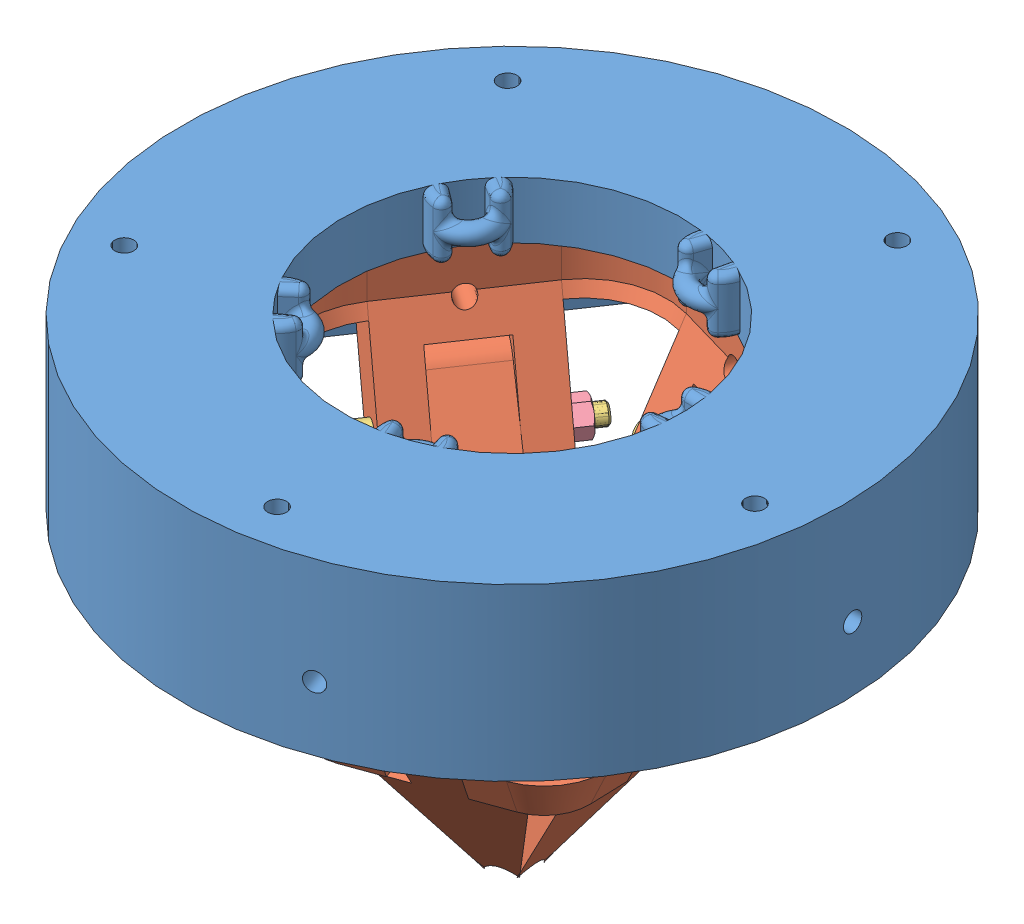
SolidWorks assembly Manipulator - pentagon v1, configuration Default. Lengths in mm.
Overall size (183.82 130.58 183.76).
19 component instances, 6 part files, 44 mates.
Components (placement in the parent):
- Rope-1: Rope [Default] at (264.0105 254.2057 492.1032) x (-0.958589 0 0.284792) z (-0.284792 0 -0.958589) (suppressed, hidden)
- Case - Pentagon-1: Case - Pentagon [Default] at (264.0105 559.0057 492.1032) x (-0.999444 0 0.033344) z (0.033344 0 0.999444) size (173.99 45.12 173.99)
- CASE inside - Pentagon-v1-1: CASE inside - Pentagon-v1 [smaller1] at (264.0101 394.9213 492.103) x (0.828166 0 0.560482) z (-0.560482 0 0.828166) size (130.58 68.58 133.51)
- CASE inside - Pentagon-v1-2: CASE inside - Pentagon-v1 [inside1] at (263.4329 424.6493 494.1041) x (-0.273614 0.158855 0.948631) z (-0.960832 0 -0.277133) size (38.83 92.43 30.94)
- CASE inside - Pentagon-v1-3: CASE inside - Pentagon-v1 [inside1] at (261.9292 424.649 492.1724) x (-0.986754 0.158847 0.032921) z (-0.033344 0 -0.999444) size (38.83 92.43 30.94)
- CASE inside - Pentagon-v1-4: CASE inside - Pentagon-v1 [inside1] at (263.3011 424.649 490.1453) x (-0.336234 0.158847 -0.928286) z (0.940224 0 -0.340558) size (38.83 92.43 30.94)
- CASE inside - Pentagon-v1-5: CASE inside - Pentagon-v1 [inside1] at (265.6533 424.6493 490.8232) x (0.778949 0.158855 -0.606632) z (0.614435 0 0.788968) size (38.83 92.43 30.94)
- CASE inside - Pentagon-v1-6: CASE inside - Pentagon-v1 [inside1] at (265.7353 424.6496 493.2705) x (0.81765 0.15886 0.553365) z (-0.560482 0 0.828166) size (38.83 92.43 30.94)
- socket head cap screw_am-1: socket head cap screw_am [B18.3.1M - 5 x 0.8 x 45 Hex SHCS -- 22CHX] at (253.2185 503.6558 444.8323) x (0.960832 0 0.277133) z (-0.275722 0.100767 0.955941) size (50 8.5 8.5)
- hex nut style 1_am-1: hex nut style 1_am [B18.2.4.1M - Hex nut, Style 1,  M5 x 0.8 --D-C] at (307.1875 503.6558 513.8445) x (0.040243 -0.999189 -0.001343) z (0.033344 0 0.999444) size (8 9.24 4.7)
- hex nut style 1_am-2: hex nut style 1_am [B18.2.4.1M - Hex nut, Style 1,  M5 x 0.8 --D-C] at (298.0301 503.6558 457.7573) x (0.277133 0 -0.960832) z (0.960832 0 0.277133) size (8 9.24 4.7)
- socket head cap screw_am-2: socket head cap screw_am [B18.3.1M - 5 x 0.8 x 45 Hex SHCS -- 22CHX] at (305.6324 503.6558 467.2321) x (0.033344 0 0.999444) z (-0.26331 0.964671 0.008785) size (50 8.5 8.5)
- socket head cap screw_am-3: socket head cap screw_am [B18.3.1M - 5 x 0.8 x 45 Hex SHCS -- 22CHX] at (300.5257 503.6558 524.0025) x (-0.940224 0 0.340558) z (-0.340519 -0.01505 -0.940117) size (50 8.5 8.5)
- hex nut style 1_am-3: hex nut style 1_am [B18.2.4.1M - Hex nut, Style 1,  M5 x 0.8 --D-C] at (256.6753 503.6558 539.8856) x (0.292493 0.512201 0.807526) z (-0.940224 0 0.340558) size (8 9.24 4.7)
- socket head cap screw_am-4: socket head cap screw_am [B18.3.1M - 5 x 0.8 x 45 Hex SHCS -- 22CHX] at (244.9557 503.6558 536.6888) x (-0.614435 0 -0.788968) z (-0.4452 0.825582 0.346714) size (50 8.5 8.5)
- hex nut style 1_am-4: hex nut style 1_am [B18.2.4.1M - Hex nut, Style 1,  M5 x 0.8 --D-C] at (216.2996 503.6558 499.8927) x (0.578301 0.680246 -0.450371) z (-0.614435 0 -0.788968) size (8 9.24 4.7)
- socket head cap screw_am-5: socket head cap screw_am [B18.3.1M - 5 x 0.8 x 45 Hex SHCS -- 22CHX] at (215.7183 503.6558 487.759) x (0.560482 0 -0.828166) z (-0.764162 -0.385483 -0.517165) size (50 8.5 8.5)
- hex nut style 1_am-5: hex nut style 1_am [B18.2.4.1M - Hex nut, Style 1,  M5 x 0.8 --D-C] at (239.224 503.6558 453.0271) x (-0.777076 0.345798 -0.525905) z (-0.560482 0 0.828166) size (8 9.24 4.7)
- 7383N345_Music_Wire_Steel_Extension_Spring_with_Hook_Ends-1: 7383N345_Music_Wire_Steel_Extension_Spring_with_Hook_Ends [7383N345] at (157.8744 518.82 551.2851) (suppressed, hidden)
Mates (geometry in assembly coordinates):
- Coincident1: coincident aligned: plane of Rope-1 through (264.0105 559.0057 492.1032) normal (0 1 0); plane of Case - Pentagon-1 through (264.0105 559.0057 492.1032) normal (0 1 0)
- Concentric1: concentric anti-aligned: cylinder of Rope-1 through (264.0105 559.0057 492.1032) axis (0 -1 0) radius 6.35; cylinder of Case - Pentagon-1 through (264.0105 544.0057 492.1032) axis (0 1 0) radius 44.6875
- Coincident2: coincident anti-aligned: plane of Case - Pentagon-1 through (214.8645 412.2562 530.3773) normal (0.788968 0 -0.614435); plane of CASE inside - Pentagon-v1-1 through (196.4311 648.9213 506.7079) normal (-0.788968 0 0.614435)
- Parallel1: parallel anti-aligned: plane of Case - Pentagon-1 through (264.0105 544.0057 492.1032) normal (0 -1 0); plane of CASE inside - Pentagon-v1-1 through (264.0101 543.5058 492.103) normal (0 1 0)
- Parallel2: parallel anti-aligned: plane of Case - Pentagon-1 through (264.0105 544.0057 492.1032) normal (0 -1 0); plane of CASE inside - Pentagon-v1-1 through (264.0101 543.5058 492.103) normal (0 1 0)
- Coincident5: coincident anti-aligned: plane of Case - Pentagon-1 through (212.4227 412.2562 457.1899) normal (0.828166 0 0.560482); plane of CASE inside - Pentagon-v1-1 through (229.2369 648.9213 432.3447) normal (-0.828166 0 -0.560482)
- Concentric3: concentric anti-aligned: cylinder of Case - Pentagon-1 through (163.3741 531.0057 423.995) axis (0.828166 0 0.560482) radius 2.5; cylinder of CASE inside - Pentagon-v1-1 through (330.8431 531.0057 537.3338) axis (-0.828166 0 -0.560482) radius 2.5
- Coincident6: coincident aligned: circle of CASE inside - Pentagon-v1-1; cylinder of CASE inside - Pentagon-1 through (290.8669 498.4684 454.8116) axis (-0.960832 0 -0.277133) radius 2.5
- Coincident7: coincident anti-aligned: plane of CASE inside - Pentagon-v1-1 through (267.3159 518.9641 450.0817) normal (0.960832 0 0.277133); plane of CASE inside - Pentagon-1 through (271.438 527.1006 435.7904) normal (-0.960832 0 -0.277133)
- Coincident8: coincident anti-aligned: plane of CASE inside - Pentagon-v1-1 through (267.3159 518.9641 450.0817) normal (0.960832 0 0.277133); plane of CASE inside - Pentagon-v1-2 through (272.0543 540.5577 433.6536) normal (-0.960832 0 -0.277133)
- Concentric4: concentric anti-aligned: cylinder of CASE inside - Pentagon-v1-1 through (251.2286 503.6558 444.2584) axis (0.960832 0 0.277133) radius 2.5; cylinder of CASE inside - Pentagon-v1-2 through (290.6326 503.6558 455.6237) axis (-0.960832 0 -0.277133) radius 2.5
- Coincident9: coincident anti-aligned: plane of CASE inside - Pentagon-v1-1 through (304.9962 518.9641 482.2617) normal (0.033344 0 0.999444); plane of CASE inside - Pentagon-v1-3 through (322.0842 540.5578 481.6916) normal (-0.033344 0 -0.999444)
- Concentric5: concentric anti-aligned: cylinder of CASE inside - Pentagon-v1-1 through (305.5633 503.6558 465.1622) axis (0.033344 0 0.999444) radius 2.5; cylinder of CASE inside - Pentagon-v1-3 through (306.9308 503.6558 506.1498) axis (-0.033344 0 -0.999444) radius 2.5
- Coincident10: coincident anti-aligned: plane of CASE inside - Pentagon-v1-1 through (286.0351 518.9641 528.0419) normal (-0.940224 0 0.340558); plane of CASE inside - Pentagon-v1-4 through (291.8578 540.5578 544.1174) normal (0.940224 0 -0.340558)
- Concentric6: concentric anti-aligned: cylinder of CASE inside - Pentagon-v1-1 through (302.473 503.6558 523.2972) axis (-0.940224 0 0.340558) radius 2.5; cylinder of CASE inside - Pentagon-v1-4 through (263.914 503.6558 537.2636) axis (0.940224 0 -0.340558) radius 2.5
- Coincident12: coincident anti-aligned: plane of CASE inside - Pentagon-v1-1 through (236.6362 518.9641 524.1557) normal (-0.614435 0 -0.788968); plane of CASE inside - Pentagon-v1-5 through (223.1466 540.5577 534.6612) normal (0.614435 0 0.788968)
- Concentric7: concentric anti-aligned: cylinder of CASE inside - Pentagon-v1-1 through (246.2283 503.6558 538.3228) axis (-0.614435 0 -0.788968) radius 2.5; cylinder of CASE inside - Pentagon-v1-5 through (221.0301 503.6558 505.967) axis (0.614435 0 0.788968) radius 2.5
- Coincident13: coincident anti-aligned: plane of CASE inside - Pentagon-v1-1 through (259.2633 394.9213 499.1168) normal (0.560482 0 -0.828166); plane of CASE inside - Pentagon-v1-6 through (210.9072 540.5576 466.3906) normal (-0.560482 0 0.828166)
- Concentric8: concentric anti-aligned: cylinder of CASE inside - Pentagon-v1-1 through (214.5575 503.6558 489.4741) axis (0.560482 0 -0.828166) radius 2.5; cylinder of CASE inside - Pentagon-v1-6 through (237.5431 503.6558 455.5107) axis (-0.560482 0 0.828166) radius 2.5
- Tangent2: tangent aligned: cylinder of Rope-1 through (264.0105 559.0057 492.1032) axis (0 -1 0) radius 6.35; curve of CASE inside - Pentagon-v1-4
- Tangent3: tangent: cylinder of Rope-1 through (264.0105 559.0057 492.1032) axis (0 -1 0) radius 6.35; curve of CASE inside - Pentagon-v1-3
- Tangent4: tangent: cylinder of Rope-1 through (264.0105 559.0057 492.1032) axis (0 -1 0) radius 6.35; curve of CASE inside - Pentagon-v1-2
- Tangent5: tangent: cylinder of Rope-1 through (264.0105 559.0057 492.1032) axis (0 -1 0) radius 6.35; curve of CASE inside - Pentagon-v1-6
- Tangent6: tangent: cylinder of Rope-1 through (264.0105 559.0057 492.1032) axis (0 -1 0) radius 6.35; curve of CASE inside - Pentagon-v1-5
- Concentric10: concentric anti-aligned: cylinder of CASE inside - Pentagon-v1-1 through (251.2286 503.6558 444.2584) axis (0.960832 0 0.277133) radius 2.5; cylinder of socket head cap screw_am-1 through (222.7121 503.6558 436.0334) axis (-0.960832 0 -0.277133) radius 2.5
- Coincident14: coincident anti-aligned: plane of CASE inside - Pentagon-v1-1 through (257.7076 518.9641 447.3104) normal (-0.960832 0 -0.277133); plane of socket head cap screw_am-1 through (258.1414 507.8841 445.8065) normal (0.960832 0 0.277133)
- Concentric11: concentric anti-aligned: cylinder of socket head cap screw_am-1 through (222.7121 503.6558 436.0334) axis (-0.960832 0 -0.277133) radius 2.5; cylinder of hex nut style 1_am-2 through (293.5142 503.6558 456.4548) axis (0.960832 0 0.277133) radius 2.1
- Coincident15: coincident anti-aligned: plane of CASE inside - Pentagon-v1-1 through (293.1991 518.9641 457.5472) normal (0.960832 0 0.277133); plane of hex nut style 1_am-2 through (293.5142 508.2746 456.4548) normal (-0.960832 0 -0.277133)
- Concentric12: concentric anti-aligned: cylinder of CASE inside - Pentagon-v1-1 through (305.5633 503.6558 465.1622) axis (0.033344 0 0.999444) radius 2.5; cylinder of socket head cap screw_am-2 through (304.5737 503.6558 435.4998) axis (-0.033344 0 -0.999444) radius 2.5
- Coincident16: coincident anti-aligned: plane of CASE inside - Pentagon-v1-1 through (304.6628 518.9641 472.2672) normal (-0.033344 0 -0.999444); plane of socket head cap screw_am-2 through (309.8967 504.7755 472.0926) normal (0.033344 0 0.999444)
- Concentric13: concentric anti-aligned: circle of hex nut style 1_am-1; cylinder of socket head cap screw_am-2 through (304.5737 503.6558 435.4998) axis (-0.033344 0 -0.999444) radius 2.5
- Coincident17: coincident anti-aligned: plane of CASE inside - Pentagon-v1-1 through (305.8945 518.9641 509.185) normal (0.033344 0 0.999444); plane of hex nut style 1_am-1 through (311.6433 503.8418 508.9932) normal (-0.033344 0 -0.999444)
- Concentric14: concentric anti-aligned: cylinder of CASE inside - Pentagon-v1-1 through (302.473 503.6558 523.2972) axis (-0.940224 0 0.340558) radius 2.5; cylinder of socket head cap screw_am-3 through (330.3778 503.6558 513.1898) axis (0.940224 0 -0.340558) radius 2.5
- Coincident18: coincident anti-aligned: plane of CASE inside - Pentagon-v1-1 through (295.4374 518.9641 524.6364) normal (0.940224 0 -0.340558); plane of socket head cap screw_am-3 through (295.8028 507.9053 525.6452) normal (-0.940224 0 0.340558)
- Concentric15: concentric anti-aligned: cylinder of socket head cap screw_am-3 through (330.3778 503.6558 513.1898) axis (0.940224 0 -0.340558) radius 2.5; cylinder of hex nut style 1_am-3 through (261.0943 503.6558 538.285) axis (-0.940224 0 0.340558) radius 2.1
- Coincident19: coincident anti-aligned: plane of CASE inside - Pentagon-v1-1 through (260.7071 518.9641 537.216) normal (-0.940224 0 0.340558); plane of hex nut style 1_am-3 through (260.2886 507.6227 536.0606) normal (0.940224 0 -0.340558)
- Concentric16: concentric anti-aligned: cylinder of CASE inside - Pentagon-v1-1 through (246.2283 503.6558 538.3228) axis (-0.614435 0 -0.788968) radius 2.5; cylinder of socket head cap screw_am-4 through (264.464 503.6558 561.7386) axis (0.614435 0 0.788968) radius 2.5
- Coincident22: coincident anti-aligned: plane of CASE inside - Pentagon-v1-1 through (242.7806 518.9641 532.0454) normal (0.614435 0 0.788968); plane of socket head cap screw_am-4 through (239.1153 501.2576 534.8999) normal (-0.614435 0 -0.788968)
- Concentric17: concentric anti-aligned: cylinder of socket head cap screw_am-4 through (264.464 503.6558 561.7386) axis (0.614435 0 0.788968) radius 2.5; cylinder of hex nut style 1_am-4 through (219.1874 503.6558 503.6009) axis (-0.614435 0 -0.788968) radius 2.1
- Coincident23: coincident anti-aligned: plane of CASE inside - Pentagon-v1-1 through (220.0844 518.9641 502.9023) normal (-0.614435 0 -0.788968); plane of hex nut style 1_am-4 through (221.6663 500.2703 501.6704) normal (0.614435 0 0.788968)
- Concentric18: concentric anti-aligned: cylinder of CASE inside - Pentagon-v1-1 through (214.5575 503.6558 489.4741) axis (0.560482 0 -0.828166) radius 2.5; cylinder of socket head cap screw_am-5 through (197.923 503.6558 514.0532) axis (-0.560482 0 0.828166) radius 2.5
- Coincident24: coincident anti-aligned: plane of CASE inside - Pentagon-v1-1 through (219.4623 518.9641 484.2554) normal (-0.560482 0 0.828166); plane of socket head cap screw_am-5 through (219.8775 499.7342 484.5364) normal (0.560482 0 -0.828166)
- Coincident25: coincident anti-aligned: plane of CASE inside - Pentagon-v1-1 through (240.1656 518.9641 453.6643) normal (0.560482 0 -0.828166); plane of hex nut style 1_am-5 through (237.9013 499.3219 452.1319) normal (-0.560482 0 0.828166)
- Concentric19: concentric aligned: cylinder of socket head cap screw_am-5 through (197.923 503.6558 514.0532) axis (-0.560482 0 0.828166) radius 2.5; cylinder of hex nut style 1_am-5 through (241.8583 503.6558 449.1347) axis (-0.560482 0 0.828166) radius 2.1
